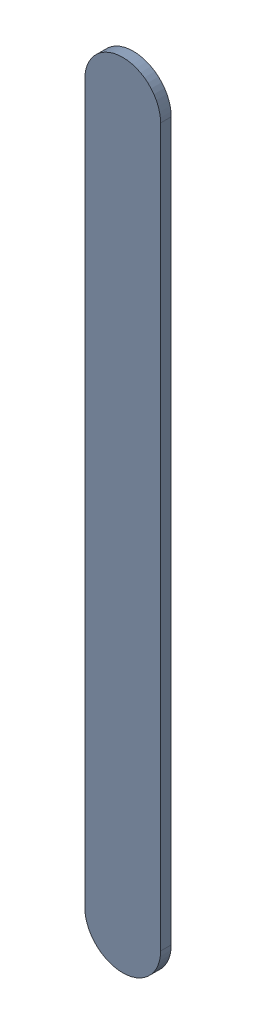
SolidWorks assembly Track (19mm,53.5mm)(19mm,55.903mm) on Top Layer, configuration Predeterminado. Lengths in mm.
Overall size (0.25 2.66 0.04).
2 component instances, 1 part files, 0 mates.
Components (placement in the parent):
- Track (19mm,53.5mm)(19mm,55.903mm) on Top Layer-1-1: Track (19mm,53.5mm)(19mm,55.903mm) on Top Layer-1 [Predeterminado] at (-68.317 -44.187 -0.0457) size (0.25 2.66 0.04)
  - Track (19mm,53.5mm)(19mm,55.903mm) on Top Layer-Part-1-1: Track (19mm,53.5mm)(19mm,55.903mm) on Top Layer-Part-1 [Predeterminado] at origin size (0.25 2.66 0.04)
